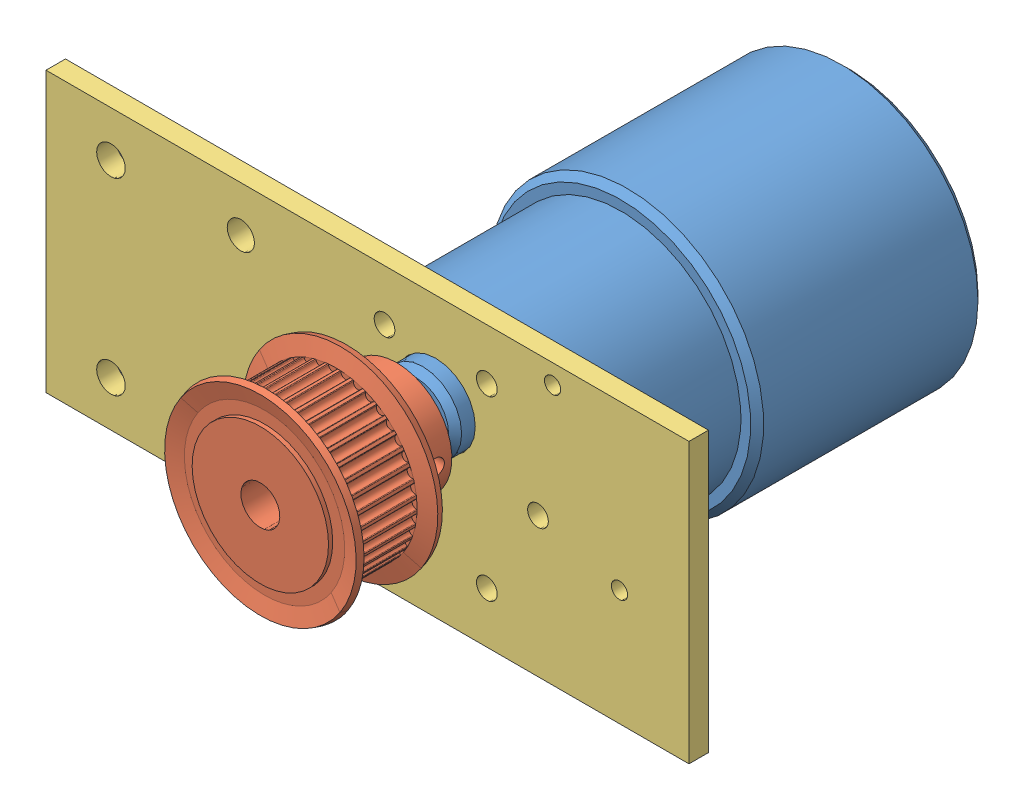
SolidWorks assembly x軸移動機構, configuration ﾃﾞﾌｫﾙﾄ. Lengths in mm.
Overall size (91.2 86 90.5).
4 component instances, 3 part files, 5 mates.
Components (placement in the parent):
- ツカサDCモーター-2: ツカサDCモーター [ﾃﾞﾌｫﾙﾄ] at (-72.9545 -50.72 -48.1751) size (42 42 81.5)
- GPA40GT2090_B_H6-1: GPA40GT2090_B_H6 [Default] at (-72.9545 -43.72 35.6749) x (0 0 -1) z (0.831138 -0.556067 0) size (21 30 30)
  - _GPA40GT2090_B_H6_b_2-1: _GPA40GT2090_B_H6_b_2 [Default] at origin size (21 30 30)
- X軸モーターマウント-1: X軸モーターマウント [ﾃﾞﾌｫﾙﾄ] at (-68.4545 -8.22 12.3249) x (0 -1 0) z (0 0 1) size (86 91.2 3)
Mates (geometry in assembly coordinates):
- 同心円1: concentric: cylinder of ツカサDCモーター-2 through (-72.9545 -43.72 33.3249) axis (0 0 -1) radius 3; cylinder of GPA40GT2090_B_H6-1/_GPA40GT2090_B_H6_b_2-1 through (-72.9545 -43.72 21.3249) axis (0 0 1) radius 3
- 一致1: coincident: circle of ツカサDCモーター-2; circle of GPA40GT2090_B_H6-1/_GPA40GT2090_B_H6_b_2-1
- 一致2: coincident: plane of ツカサDCモーター-2 through (-72.9545 -50.72 12.3249) normal (0 0 1); plane of X軸モーターマウント-1 through (-68.4545 -8.22 12.3249) normal (0 0 -1)
- 同心円2: concentric: cylinder of ツカサDCモーター-2 through (-72.9545 -43.72 18.3249) axis (0 0 -1) radius 6; circle of X軸モーターマウント-1
- 同心円3: concentric: circle of ツカサDCモーター-2; cylinder of X軸モーターマウント-1 through (-65.0795 -37.0801 5.3249) axis (0 0 1) radius 1.6
